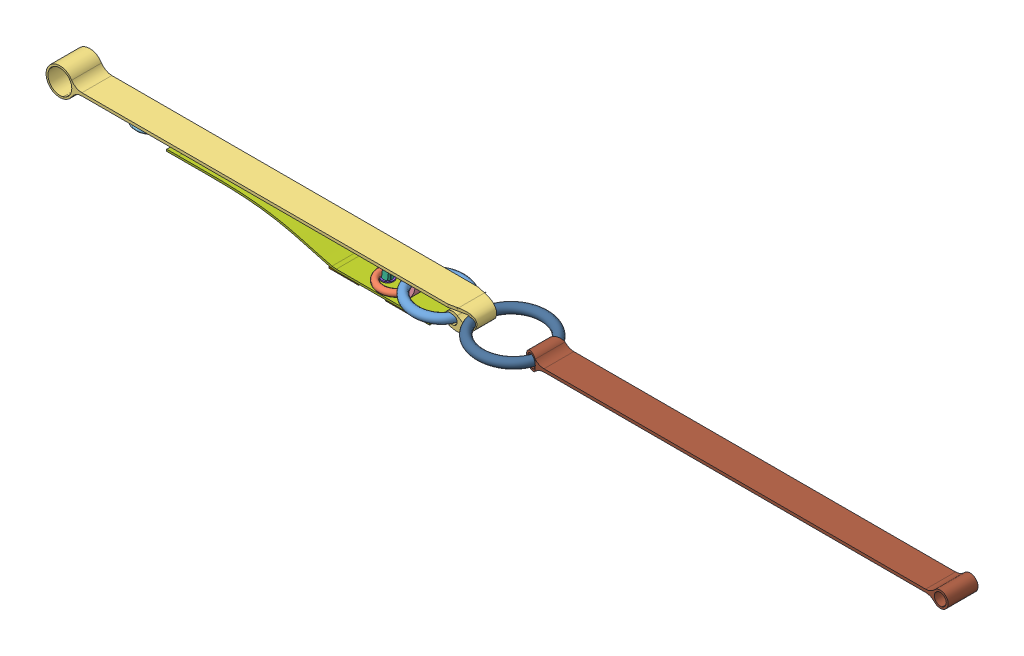
SolidWorks assembly 3-ring_assy_V1, configuration Default. Lengths in mm.
Overall size (479.53 98.88 39.69).
13 component instances, 11 part files, 33 mates.
Components (placement in the parent):
- H3860S_NO3_Ring-1: H3860S_NO3_Ring [Default] at (-51.3677 -8.0145 0) x (0 0 1) z (0.109189 0.994021 0) size (31.35 31.35 4.56)
- H3880S_NO4_Ring-1: H3880S_NO4_Ring [Default] at (-78.0917 -10.3227 0) x (0 0 1) z (0 1 0) size (20.24 20.24 3.37)
- webbing_base_V1-1: webbing_base_V1 [Default] at (-148.7292 0 0) x (1 0 0) z (0 0 -1) size (226.78 20.16 15.88)
- webbing_small_V1-2: webbing_small_V1 [Default] at (-116.3544 -1.524 0) x (1 0 0) z (0 0 -1) size (81.41 12.13 12.7)
- yellow_cord_V1.1-1: yellow_cord_V1.1 [Default] at (-205.5518 -5.8886 0) x (0 1 0) z (0 0 -1) size (98.88 160.58 9.08)
- nylon_loop_V1-1: nylon_loop_V1 [Default] at (-91.6172 -16.6947 0) x (0 0 1) z (0 -1 0) size (4.82 25.4 15.18)
- grommet_assy-1: grommet_assy [Default] at (-227.0655 159.1333 21.2356) x (0 0 -1) z (0 -1 0) size (19.05 139.7 16.13)
  - webbing_grommet_V1-1: webbing_grommet_V1 [Default] at (21.2356 27.4983 171.1427) size (19.05 139.7 11.24)
  - grommet_V1-1: grommet_V1 [Default] at (21.2356 135.4483 170.5712) x (1 0 0) z (0 -1 0) size (10.16 2.6 10.16)
  - yellow_cord_guide-1: yellow_cord_guide [Default] at (21.2356 159.2608 174.1907) x (1 0 0) z (0 -1 0) size (18.04 4.89 15.88)
- H3840B_NO2_Ring-1: H3840B_NO2_Ring [Default] at (-25.4211 -5.2162 0) x (0.999637 -0.026926 0) z (0.026926 0.999637 0) size (39.69 39.69 4.76)
- webbing_top_V1-3: webbing_top_V1 [Default] at (100.8035 -5.7956 0) size (226.82 8.38 15.88)
- yellow_cord_guide-2: yellow_cord_guide [Default] at (-97.9672 -15.0574 0) x (0 0 -1) z (-1 0 0) size (18.04 4.89 15.88)
Mates (geometry in assembly coordinates):
- Parallel30: parallel anti-aligned: plane of webbing_base_V1-1 through (-148.7292 0 0) normal (0 0 -1); plane of assembly through (0 0 0) normal (0 0 1)
- Coincident83: coincident anti-aligned: plane of webbing_base_V1-1 through (-148.7292 -1.524 0) normal (0 -1 0); plane of webbing_small_V1-2 through (-116.3544 -1.524 0) normal (0 1 0)
- Parallel31: parallel aligned: plane of webbing_base_V1-1 through (-250.3292 -1.524 7.9375) normal (0 0 1); plane of webbing_small_V1-2 through (-154.4544 -2.54 6.35) normal (0 0 1)
- Tangent33: tangent: torus of H3880S_NO4_Ring-1; plane of webbing_small_V1-2 through (-123.1879 -1.7048 0.0803) normal (0 -1 0)
- Angle1: planar angle = 0 rad anti-aligned: cylinder of nylon_loop_V1-1 through (-90.0297 -14.986 0) axis (-1 0 0) radius 1.5875; cylinder of yellow_cord_V1.1-1 through (-96.4019 -15.4224 0) axis (1 0 0) radius 1.5875
- Parallel32: parallel aligned: plane of H3880S_NO4_Ring-1 through (-78.0917 -10.3227 0) normal (0 1 0); plane of assembly through (0 0 0) normal (0 1 0)
- Tangent35: tangent: torus of H3880S_NO4_Ring-1; cylinder of webbing_small_V1-2 through (-78.2544 -10.16 -6.35) axis (0 0 1) radius 1.524
- Tangent37: tangent: torus of H3860S_NO3_Ring-1; cylinder of webbing_small_V1-2 through (-78.2544 -5.08 -6.35) axis (0 0 1) radius 2.54
- Coincident84: coincident anti-aligned: plane of H3880S_NO4_Ring-1 through (-78.0917 -10.3227 0) normal (0 0 1); plane of webbing_small_V1-2 through (-116.3544 -1.524 0) normal (0 0 -1)
- Coincident85: coincident aligned: plane of webbing_base_V1-1 through (-148.7292 0 0) normal (0 0 -1); plane of webbing_small_V1-2 through (-116.3544 -1.524 0) normal (0 0 -1)
- Coincident86: coincident aligned: plane of H3860S_NO3_Ring-1 through (-51.3677 -8.0145 0) normal (0 0 1); plane of H3880S_NO4_Ring-1 through (-78.0917 -10.3227 0) normal (0 0 1)
- Tangent38: tangent: torus of H3860S_NO3_Ring-1; cylinder of webbing_base_V1-1 through (-51.3642 -8.1454 7.9375) axis (0 0 -1) radius 2.413
- Parallel34: parallel aligned: plane of webbing_small_V1-2 through (-116.3544 -2.54 0) normal (0 -1 0); plane of grommet_assy-1/webbing_grommet_V1-1 through (-199.5672 -13.0254 0) normal (0 -1 0)
- Coincident91: coincident anti-aligned: plane of webbing_small_V1-2 through (-116.3544 -2.54 0) normal (0 -1 0); plane of nylon_loop_V1-1 through (-91.6172 -2.54 0.8958) normal (0 1 0)
- Coincident92: coincident anti-aligned: plane of webbing_base_V1-1 through (-148.7292 0 0) normal (0 0 -1); plane of nylon_loop_V1-1 through (-91.6172 -16.6947 0) normal (0 0 1)
- Coincident93: coincident anti-aligned: plane of H3880S_NO4_Ring-1 through (-93.2047 -10.3227 0) normal (1 0 0); plane of nylon_loop_V1-1 through (-93.2047 -16.6947 0) normal (-1 0 0)
- Coincident95: coincident: line of yellow_cord_V1.1-1 through (-96.1522 -15.4224 0) axis (1 0 0); point of nylon_loop_V1-1
- Distance1: distance = 25.4 mm: point of nylon_loop_V1-1; plane of yellow_cord_V1.1-1 through (-66.2172 -15.4224 0) normal (1 0 0)
- Parallel35: parallel anti-aligned: plane of webbing_small_V1-2 through (-116.3544 -2.54 0) normal (0 -1 0); plane of yellow_cord_V1.1-1 through (-205.5518 -5.8886 0) normal (0 1 0)
- Concentric6: concentric anti-aligned: line of nylon_loop_V1-1 through (44.704 -91.6172 -14.6627) axis (0 0 -1); cylinder of grommet_assy-1/grommet_V1-1 through (-91.6172 -13.0254 0) axis (0 1 0) radius 2.3813
- Tangent41: tangent anti-aligned: torus of H3880S_NO4_Ring-1; plane of grommet_assy-1/webbing_grommet_V1-1 through (-199.5672 -12.0094 0) normal (0 1 0)
- Coincident97: coincident aligned: plane of webbing_base_V1-1 through (-148.7292 0 0) normal (0 1 0); plane of assembly through (0 0 0) normal (0 1 0)
- Coincident98: coincident aligned: plane of H3860S_NO3_Ring-1 through (-51.3677 -8.0145 0) normal (0 0 1); plane of assembly through (0 0 0) normal (0 0 1)
- Coincident99: coincident anti-aligned: plane of H3840B_NO2_Ring-1 through (-25.4211 -5.2162 0) normal (0 0 -1); plane of assembly through (0 0 0) normal (0 0 1)
- Tangent43: tangent: cylinder of webbing_base_V1-1 through (-42.883 -4.7148 7.9375) axis (0 0 -1) radius 2.413; torus of H3840B_NO2_Ring-1
- Tangent45: tangent: torus of H3840B_NO2_Ring-1; cylinder of webbing_top_V1-3 through (-8.4165 -5.0336 -7.9375) axis (0 0 1) radius 3.175
- Parallel37: parallel aligned: plane of webbing_small_V1-2 through (-116.3544 -2.54 0) normal (0 -1 0); plane of webbing_top_V1-3 through (100.8035 -5.7956 0) normal (0 -1 0)
- Coincident101: coincident aligned: plane of webbing_base_V1-1 through (-250.3292 -1.524 -7.9375) normal (0 0 -1); plane of webbing_top_V1-3 through (-0.7965 -4.2716 -7.9375) normal (0 0 -1)
- Coincident104: coincident anti-aligned: plane of grommet_assy-1/webbing_grommet_V1-1 through (-199.5672 -13.0254 0) normal (0 -1 0); plane of yellow_cord_guide-2 through (-113.8422 -13.0254 -2.032) normal (0 1 0)
- Coincident105: coincident: plane of grommet_assy-1/webbing_grommet_V1-1 through (-199.5672 -13.0254 -9.525) normal (0 0 -1); plane of yellow_cord_guide-2 through (-113.8422 -14.0414 -9.0208) normal (0 0 -1)
- Perpendicular1: perpendicular: plane of yellow_cord_V1.1-1 through (-205.5518 -5.8886 0) normal (0 0 1); plane of grommet_assy-1/webbing_grommet_V1-1 through (-199.5672 -13.0254 0) normal (0 -1 0)
- Distance2: distance = 14.2875 mm anti-aligned: plane of yellow_cord_guide-2 through (-97.9672 -15.0574 0) normal (1 0 0); plane of grommet_assy-1/yellow_cord_guide-1 through (-83.6797 -15.0574 0) normal (-1 0 0)
- Coincident109: coincident: plane of grommet_assy-1/webbing_grommet_V1-1 through (-199.5672 -12.0094 0) normal (0 0 -1); plane of yellow_cord_guide-2 through (-97.9672 -15.0574 0) normal (0 0 -1)
